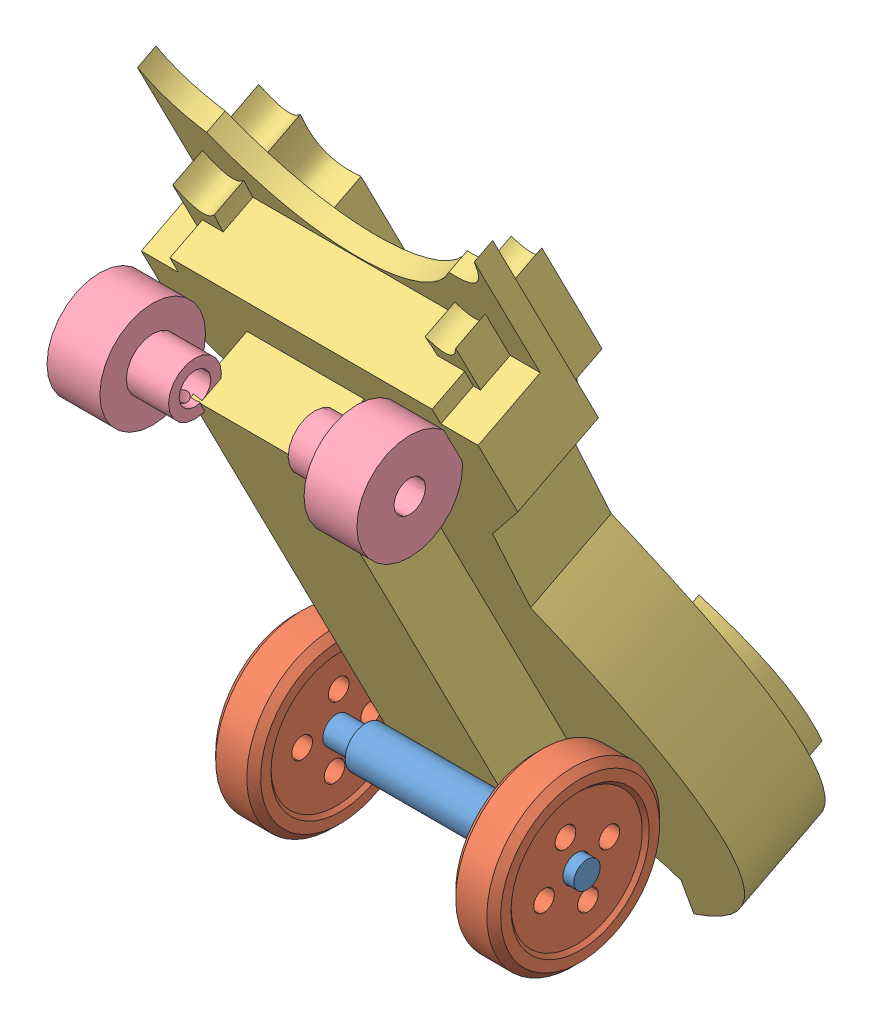
SolidWorks assembly final batmobile, configuration Default. Lengths in mm.
Overall size (1101.98 2400.62 1603.92).
7 component instances, 4 part files, 3 mates.
Components (placement in the parent):
- front assmbly-1: front assmbly [Default] at (-152.2965 37.2657 62.7686) size (844.88 635.56 635.56)
  - Part2-1: Part2 [Default] at (292.0461 432.0687 660.3918) size (840 120 120)
  - wheel + tire-1: wheel + tire [Default] at (627.0952 432.0687 660.3918) x (0 -0.325618 0.945501) z (-1 0 0) size (500 500 130)
  - wheel + tire-2: wheel + tire [Default] at (-67.832 432.0687 660.3918) x (0 -0.060971 -0.99814) z (1 0 0) size (500 500 130)
- chassis finalll-1: chassis finalll [Default] at (141.2825 1001.6384 601.8439) x (0 0.890041 0.45588) z (0 -0.45588 0.890041) size (2405.16 1101.98 570.15)
- wheel big updated-1: wheel big updated [Default] at (-224.9644 1649.3846 1251.9456) x (0 0 1) z (-1 0 0) size (306 306 275.4)
- wheel big updated-2: wheel big updated [Default] at (437.277 1648.949 1210.7323) x (0 0 -1) z (1 0 0) size (306 306 275.4)
Mates (geometry in assembly coordinates):
- Tangent10: tangent: cylinder of front assmbly-1/Part2-1 through (359.7495 469.3344 723.1604) axis (-1 0 0) radius 60; plane of chassis finalll-1 through (85.3399 554.1096 699.1698) normal (0 -0.45588 0.890041)
- Tangent11: tangent: cylinder of front assmbly-1/Part2-1 through (359.7495 469.3344 723.1604) axis (-1 0 0) radius 60; plane of chassis finalll-1 through (85.3399 638.207 534.9815) normal (0 -0.45588 0.890041)
- Coincident15: coincident: point of chassis finalll-1; curve of wheel big updated-1
